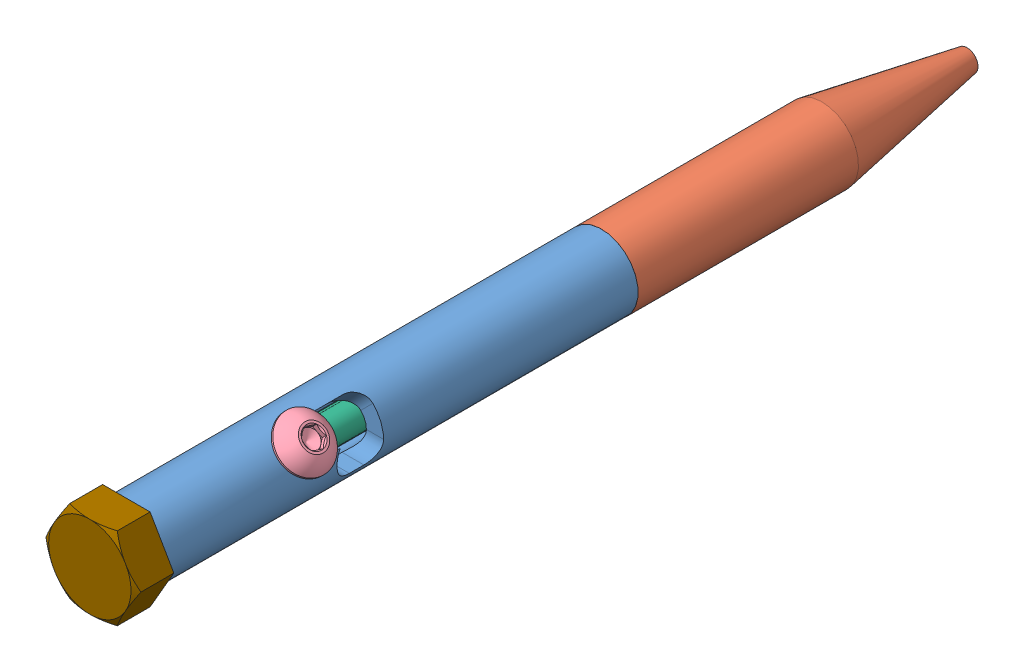
SolidWorks assembly Pen Assembly, configuration Default. Lengths in mm.
Overall size (19.31 19.31 152.4).
10 component instances, 9 part files, 11 mates.
Components (placement in the parent):
- Pen Shaft-1: Pen Shaft [Default] at (12.8073 62.304 63.1553) size (12.7 12.7 82.55)
- Pen Top-1: Pen Top [Default] at (12.8073 62.304 75.8553) x (-0.923728 -0.383049 0) z (0 0 -1) size (12.7 12.7 76.2)
- Slider Cylinder-1: Slider Cylinder [Default] at (12.8073 62.304 125.7504) x (0.707107 -0.707107 0) z (0 0 -1) size (6.35 6.35 12.7)
- 10-24 0.375in BHCS-1: 10-24 0.375in BHCS [92949A240] at (14.8369 64.3335 119.4004) x (0.518622 -0.518622 -0.679752) z (0.707107 0.707107 0) size (9.17 9.17 12.27)
- Pen inkwell assembly-1: Pen inkwell assembly [Default] at (-12.86 42.3552 33.6163) x (1 0 0) z (0 1 0) size (6.31 113.28 6.31)
  - Pen ink tip-1: Pen ink tip [Default] at (25.6673 5.0658 19.9488) size (5 28 5)
  - Pen inkwell-1: Pen inkwell [Default] at (25.6673 -78.9342 19.9488) size (5 89 5)
  - pen roller ball-1: pen roller ball [Default] at (25.6673 33.0658 19.9488) x (0.127408 -0.669313 0.731975) z (-0.328988 -0.724728 -0.605422) size (1 1 1)
  - pen inkwell cap-1: pen inkwell cap [Default] at (25.6673 -75.9342 19.9488) x (-0.950016 0 -0.312203) z (-0.312203 0 0.950016) size (5 3.5 5)
- 0.375-16 0.5in Hex Head-1: 0.375-16 0.5in Hex Head [92620A619] at (12.8073 62.304 142.5303) x (0 0 -1) z (0 -1 0) size (19.05 16.5 14.29)
Mates (geometry in assembly coordinates):
- Coincident2: coincident anti-aligned: plane of Pen Shaft-1 through (12.8073 62.304 63.1553) normal (0 0 -1); plane of Pen Top-1 through (12.8073 62.304 63.1553) normal (0 0 1)
- Concentric1: concentric aligned: circle of Pen Shaft-1; circle of Pen Top-1
- Concentric4: concentric anti-aligned: cylinder of Pen Shaft-1 through (12.8073 62.304 145.7053) axis (0 0 -1) radius 3.3655; cylinder of Slider Cylinder-1 through (12.8073 62.304 113.0504) axis (0 0 1) radius 3.175
- Coincident5: coincident anti-aligned: plane of Slider Cylinder-1 through (12.8073 62.304 113.0504) normal (0 0 -1); plane of Pen inkwell assembly-1/pen inkwell cap-1 through (12.8073 62.304 113.0504) normal (0 0 1)
- Concentric7: concentric anti-aligned: cylinder of Pen Shaft-1 through (12.8073 62.304 145.7053) axis (0 0 -1) radius 3.3655; cylinder of Pen inkwell assembly-1/Pen inkwell-1 through (12.8073 62.304 23.5504) axis (0 0 1) radius 2.5
- Concentric8: concentric anti-aligned: cylinder of Slider Cylinder-1 through (10.5623 60.0589 119.4004) axis (-0.707107 -0.707107 0) radius 1.8986; cylinder of 10-24 0.375in BHCS-1 through (19.1115 68.6081 119.4004) axis (0.707107 0.707107 0) radius 2.413
- Concentric9: concentric anti-aligned: cylinder of Pen Shaft-1 through (12.8073 62.304 145.7053) axis (0 0 1) radius 3.9688; cylinder of 0.375-16 0.5in Hex Head-1 through (12.8073 62.304 145.7053) axis (0 0 -1) radius 4.7625
- Coincident6: coincident anti-aligned: plane of Pen Shaft-1 through (12.8073 62.304 145.7053) normal (0 0 1); plane of 0.375-16 0.5in Hex Head-1 through (16.9318 55.1602 145.7053) normal (0 0 -1)
- Coincident7: coincident: plane of Pen Shaft-1 through (12.8073 62.304 63.1553) normal (0 1 0); line of 0.375-16 0.5in Hex Head-1 through (21.0562 62.304 151.4172) axis (0 0 -1)
- Tangent17: tangent: curve of Pen Shaft-1; circle of 10-24 0.375in BHCS-1
- Tangent18: tangent: curve of Pen Shaft-1; circle of 10-24 0.375in BHCS-1
